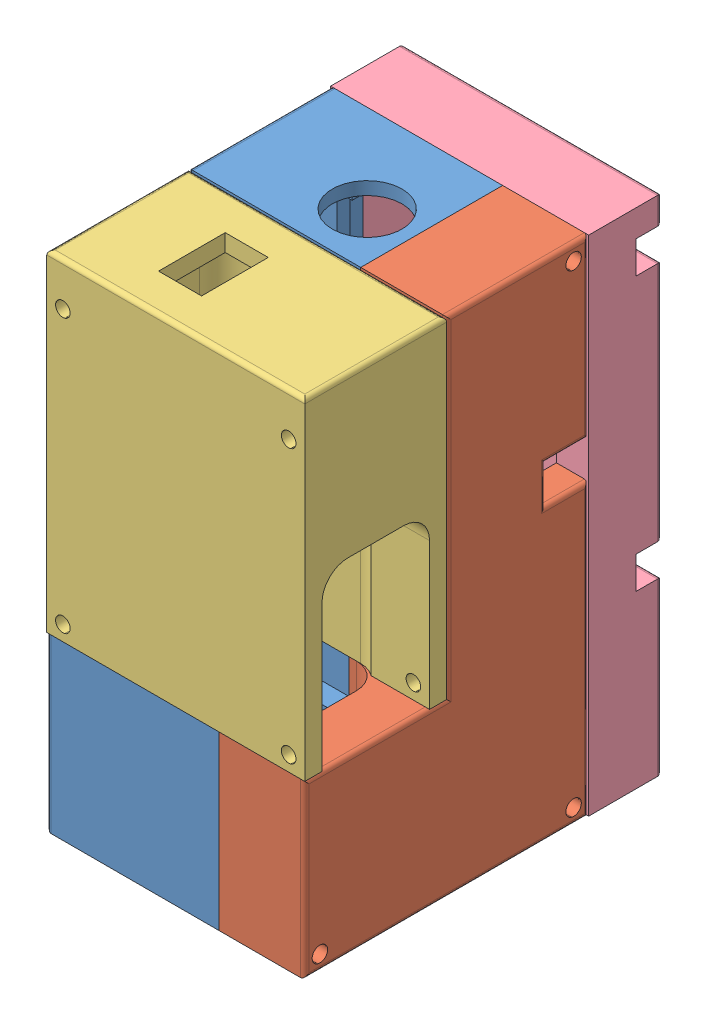
SolidWorks assembly RESS_Case, configuration ﾃﾞﾌｫﾙﾄ. Lengths in mm.
Overall size (60 117 83).
4 component instances, 4 part files, 10 mates.
Components (placement in the parent):
- RESS_Body_1-1: RESS_Body_1 [Default] at (-54.0774 -35.9003 -130.2658) size (40 117 66)
- RESS_Body_2-1: RESS_Body_2 [Default] at (-54.0774 -35.9003 -130.2658) size (20 117 66)
- RESS_Battery_Cover-1: RESS_Battery_Cover [Default] at (-24.0774 -20.9003 -113.7658) x (-1 0 0) z (0 0 -1) size (60 77 33)
- RESS_Body_Cover-2: RESS_Body_Cover [Default] at (-24.0774 -2.4003 -180.2658) x (0 1 0) z (0 0 1) size (117 60 17)
Mates (geometry in assembly coordinates):
- 同心円2: concentric aligned: cylinder of EMS_Body_Separate_1-1 through (5.9226 52.5997 -159.7658) axis (-1 0 0) radius 1.8; cylinder of EMS_Body_Separate_2-1 through (5.9226 52.5997 -159.7658) axis (-1 0 0) radius 1.8
- 同心円3: concentric aligned: cylinder of EMS_Body_Separate_1-1 through (5.9226 -57.4003 -159.7658) axis (-1 0 0) radius 1.8; cylinder of EMS_Body_Separate_2-1 through (5.9226 -57.4003 -159.7658) axis (-1 0 0) radius 1.8
- 一致4: coincident anti-aligned: plane of EMS_Body_Separate_1-1 through (-54.0774 -20.9003 -130.2658) normal (0 1 0); plane of RESS_Battery_Cover-1 through (-24.0774 -20.9003 -113.7658) normal (0 -1 0)
- 平行1: parallel anti-aligned: cylinder of EMS_Body_Separate_1-1 through (-50.3274 46.0997 -163.2658) axis (0 0 1) radius 1.8; cylinder of RESS_Battery_Cover-1 through (-50.3274 46.0997 -97.2658) axis (0 0 -1) radius 1.7
- 同心円5: concentric anti-aligned: cylinder of EMS_Body_Separate_2-1 through (2.1726 -17.4003 -163.2658) axis (0 0 1) radius 1.8; cylinder of RESS_Battery_Cover-1 through (2.1726 -17.4003 -97.2658) axis (0 0 -1) radius 1.7
- 一致5: coincident anti-aligned: plane of EMS_Body_Separate_2-1 through (5.9226 -35.9003 -130.2658) normal (0 0 1); plane of RESS_Battery_Cover-1 through (-54.0774 56.0997 -130.2658) normal (0 0 -1)
- 一致6: coincident anti-aligned: plane of EMS_Body_Separate_1-1 through (-14.0774 -35.9003 -130.2658) normal (1 0 0); plane of EMS_Body_Separate_2-1 through (-14.0774 -35.9003 -130.2658) normal (-1 0 0)
- 同心円6: concentric anti-aligned: cylinder of EMS_Body_Separate_1-1 through (-50.3274 46.0997 -163.2658) axis (0 0 1) radius 1.8; cylinder of EMS_Body_Cover-2 through (-50.3274 46.0997 -163.2658) axis (0 0 -1) radius 1.7
- 同心円7: concentric anti-aligned: cylinder of EMS_Body_Separate_2-1 through (2.1726 46.0997 -163.2658) axis (0 0 1) radius 1.8; cylinder of EMS_Body_Cover-2 through (2.1726 46.0997 -163.2658) axis (0 0 -1) radius 1.7
- 一致7: coincident anti-aligned: plane of EMS_Body_Separate_2-1 through (5.9226 -35.9003 -163.2658) normal (0 0 -1); plane of EMS_Body_Cover-2 through (-24.0774 -2.4003 -163.2658) normal (0 0 1)
